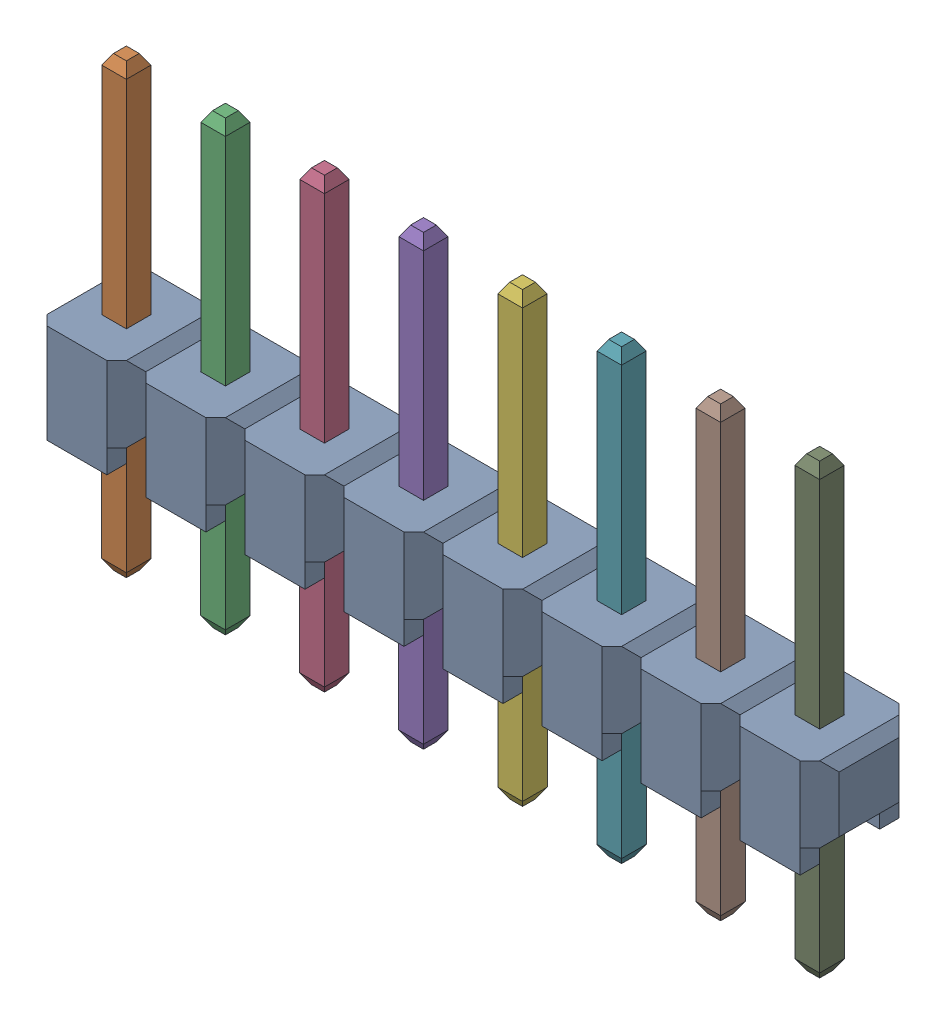
SolidWorks assembly M20-977_ASM_2, configuration Default. Lengths in mm.
Overall size (20.32 11.48 2.54).
9 component instances, 2 part files, 0 mates.
Components (placement in the parent):
- M20-977-MOULD-1: M20-977-MOULD [Default] at origin size (20.32 2.54 2.54)
- M20-977-PIN.5-1: M20-977-PIN.5 [Default] at (2.54 -5.68 0) x (1 0 0) z (0 0 -1) size (0.64 11.48 0.64)
- M20-977-PIN.5-2: M20-977-PIN.5 [Default] at (5.08 -5.68 0) x (1 0 0) z (0 0 -1) size (0.64 11.48 0.64)
- M20-977-PIN.5-3: M20-977-PIN.5 [Default] at (7.62 -5.68 0) x (1 0 0) z (0 0 -1) size (0.64 11.48 0.64)
- M20-977-PIN.5-4: M20-977-PIN.5 [Default] at (10.16 -5.68 0) x (1 0 0) z (0 0 -1) size (0.64 11.48 0.64)
- M20-977-PIN.5-5: M20-977-PIN.5 [Default] at (12.7 -5.68 0) x (1 0 0) z (0 0 -1) size (0.64 11.48 0.64)
- M20-977-PIN.5-6: M20-977-PIN.5 [Default] at (15.24 -5.68 0) x (1 0 0) z (0 0 -1) size (0.64 11.48 0.64)
- M20-977-PIN.5-7: M20-977-PIN.5 [Default] at (17.78 -5.68 0) x (1 0 0) z (0 0 -1) size (0.64 11.48 0.64)
- M20-977-PIN.5-8: M20-977-PIN.5 [Default] at (20.32 -5.68 0) x (1 0 0) z (0 0 -1) size (0.64 11.48 0.64)
